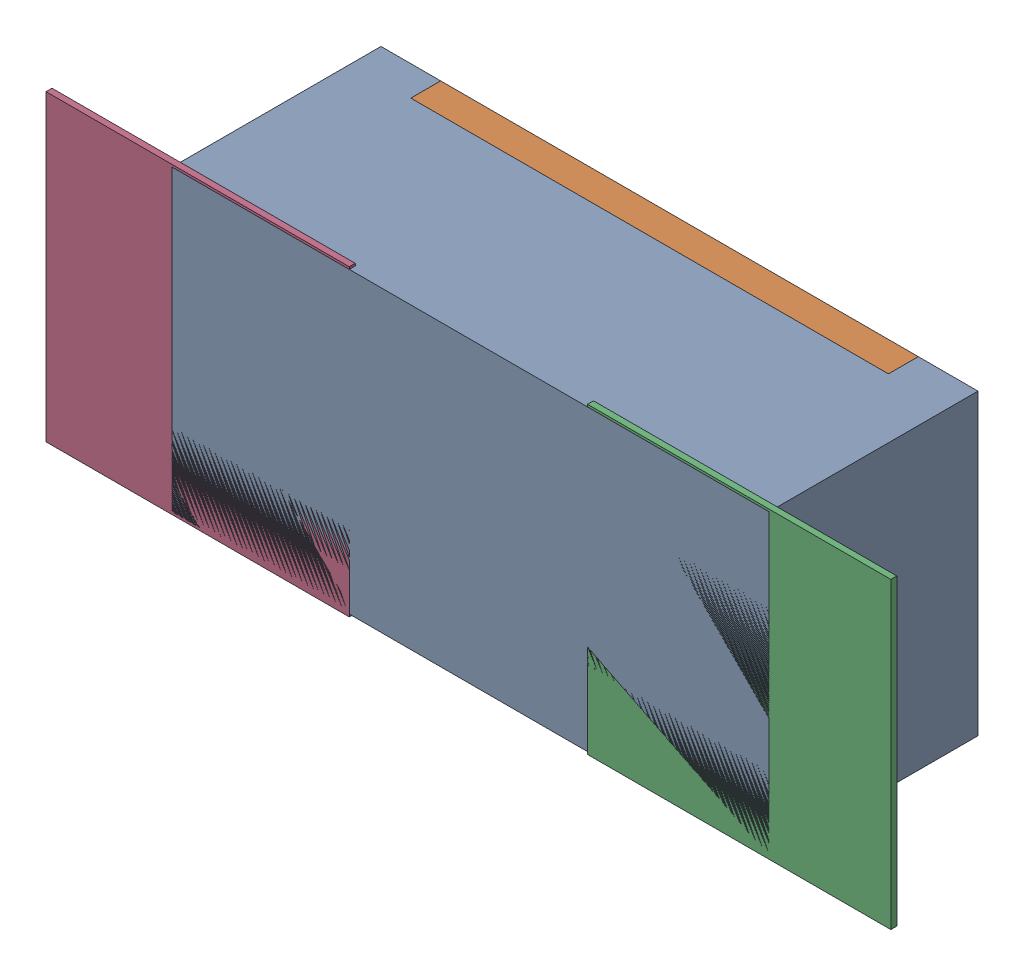
SolidWorks assembly R68, configuration Défaut. Lengths in mm.
Overall size (1.42 0.51 0.35).
5 component instances, 2 part files, 0 mates.
Components (placement in the parent):
- R0402-1: R0402 [Défaut] at (0.2032 -19.7103 -2.0818) x (1 0 0) z (0 0 -1) size (1 0.5 0.35)
- 6504207776-1: 6504207776 [Défaut] at (0.6532 -19.7104 -2.0918) size (0.51 0.51 0.01)
  - Extruded-1: Extruded [Défaut] at origin size (0.51 0.51 0.01)
- 6504207776-2: 6504207776 [Défaut] at (-0.2539 -19.7104 -2.0918) size (0.51 0.51 0.01)
  - Extruded-1: Extruded [Défaut] at origin size (0.51 0.51 0.01)
